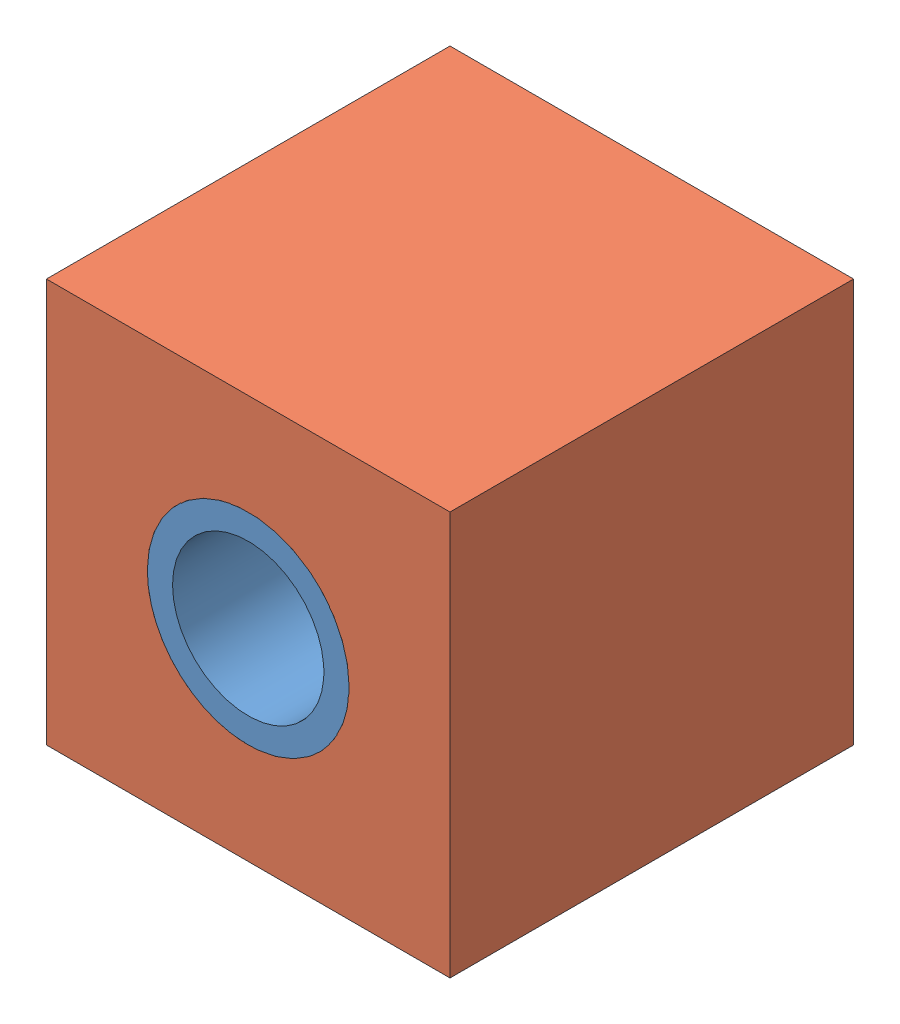
SolidWorks assembly Wood block w fitting, configuration Default. Lengths in mm.
Overall size (25.4 25.4 25.4).
2 component instances, 2 part files, 2 mates.
Components (placement in the parent):
- Bronze fitting-1: Bronze fitting [Default] at (16.3355 20.1904 11.168) size (12.7 12.7 25.4)
- Wood block-1: Wood block [Default] at (3.6355 7.4904 11.168) size (25.4 25.4 25.4)
Mates (geometry in assembly coordinates):
- Concentric1: concentric: cylinder of Bronze fitting-1 through (16.3355 20.1904 36.568) axis (0 0 -1) radius 6.35; cylinder of Wood block-1 through (16.3355 20.1904 11.168) axis (0 0 1) radius 6.35
- Coincident1: coincident anti-aligned: circle of Bronze fitting-1; circle of Wood block-1
